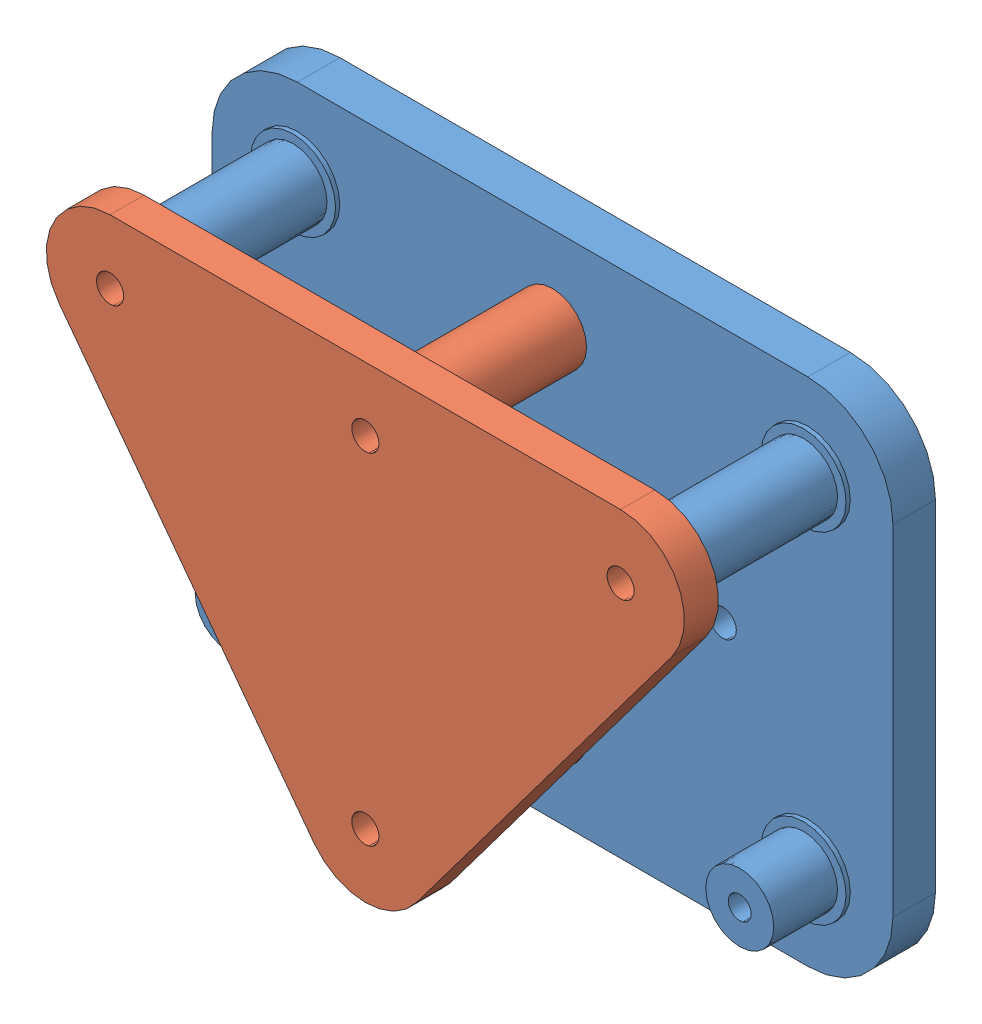
SolidWorks assembly Suspension Mounting Plate Subassembly, configuration Default. Lengths in mm.
Overall size (80 60 32).
2 component instances, 2 part files, 5 mates.
Components (placement in the parent):
- Suspension Upper Hub-1: Suspension Upper Hub [Default] at origin size (80 60 28)
- Suspension Upper Outer Hub-1: Suspension Upper Outer Hub [Default] at (0 0 18) size (75 55 22)
Mates (geometry in assembly coordinates):
- Coincident1: coordinate: point of Suspension Upper Hub-1
- InPlace1: in place: plane of Suspension Upper Hub-1 through (0 0 16.5) normal (0 0 1); plane of ? through (0 0 16.5) normal (0 0 1); moOrthogonalPlaneRef_w of Suspension Upper Hub-1 through (0 0 16.5) normal (0 0 1); plane of ? through (0 0 16.5) normal (0 1 0); plane of Suspension Upper Hub-1 through (0 0 16.5) normal (0 0 1); plane of ? through (0 0 16.5) normal (1 0 0); plane of Suspension Upper Hub-1 through (0 0 18) normal (0 0 1); unknown of Suspension Upper Outer Hub-1
- Coincident2: coincident aligned: plane of Suspension Upper Hub-1; plane of Suspension Upper Outer Hub-1
- Coincident3: coincident aligned: moOrthogonalPlaneRef_w of Suspension Upper Hub-1 through (0 0 18) normal (0 1 0); plane of Suspension Upper Outer Hub-1 through (0 0 18) normal (0 1 0)
- Coincident4: coincident anti-aligned: moOrthogonalPlaneRef_w of Suspension Upper Hub-1 through (0 0 18) normal (-1 0 0); plane of Suspension Upper Outer Hub-1 through (0 0 18) normal (1 0 0)
